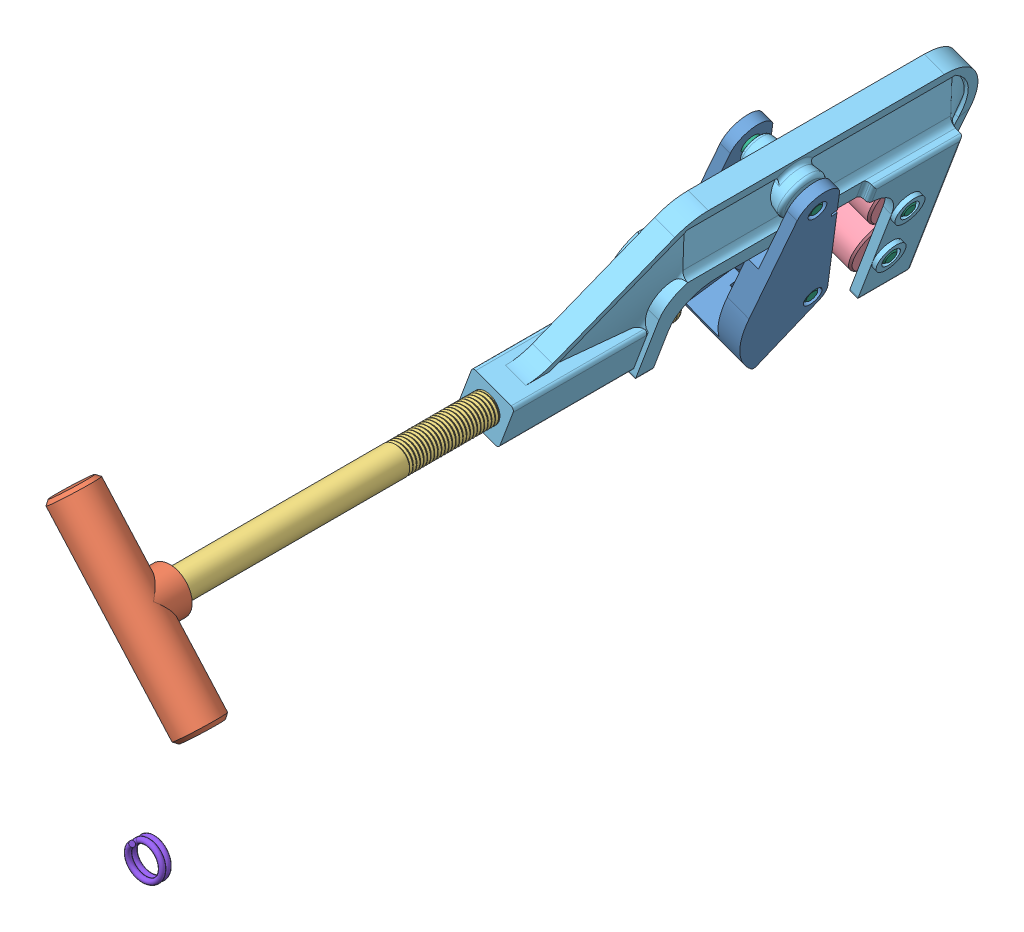
SolidWorks assembly Final_assembly, configuration Default. Lengths in mm.
Overall size (97.39 169.3 489.87).
13 component instances, 8 part files, 18 mates.
Components (placement in the parent):
- Cutter support-1: Cutter support [Default] at (104.9324 19.576 -52.4224) x (0.240047 0.640694 -0.729307) z (-0.936431 0.350851 0) size (81.78 85 46)
- Handle with shaft-1: Handle with shaft [Default] at (247.8061 39.5333 317.841) x (0 0 -1) z (-0.665294 0.746581 0) size (312.5 25 110)
  - Handle-3: Handle [Default<As Welded>] at (32.7874 88.3843 67.7523) size (31 25 110)
  - Handle shaft-1: Handle shaft [Default] at (332.7874 88.3843 122.7523) x (0 0.585455 -0.810705) z (-1 0 0) size (16 18.48 300)
- Roller-1: Roller [Default] at (107.1831 48.3849 -123.2709) x (-0.012894 -0.034413 0.999325) z (-0.936431 0.350851 0) size (30 30 30)
- Frame-2: Frame [Default] at (124.7132 137.9265 -115.2709) x (-0.936431 0.350851 0) z (0 0 1) size (45 115 255.35)
- Roller-2: Roller [Default] at (89.6157 87.0034 -123.2709) x (0.301688 0.805214 -0.510504) z (0.936431 -0.350851 0) size (30 30 30)
- Spring pin-2: Spring pin [Default] at (82.5925 89.6348 -123.2709) x (0.046179 0.123254 -0.9913) z (0.936431 -0.350851 0) size (10 10 45)
- Spring pin-3: Spring pin [Default] at (72.0669 61.5418 -123.2709) x (0.050854 0.135731 -0.98944) z (0.936431 -0.350851 0) size (10 10 45)
- Cutter-1: Cutter [Default] at (95.2554 59.3029 -76.7655) x (0.936431 -0.350851 0) z (0.114408 0.30536 0.945339) size (18 32 32)
- Spring pin-4: Spring pin [Default] at (74.1857 67.197 -76.7655) x (0.123096 0.328548 -0.936431) z (0.936431 -0.350851 0) size (10 10 45)
- Spring pin-5: Spring pin [Default] at (98.3807 131.7742 -55.2709) x (0.123096 0.328548 -0.936431) z (0.936431 -0.350851 0) size (10 10 45)
- spring-1: spring [Default] at (141.3638 -11.2103 316.7484) size (20.51 20.51 9)
Mates (geometry in assembly coordinates):
- Concentric4: concentric: cylinder of Handle with shaft-1/Handle shaft-1 through (100.1537 72.3763 285.0536) axis (0 0 -1) radius 8; cylinder of Frame-2 through (100.1537 72.3763 -5.2709) axis (0 0 1) radius 8
- Concentric5: concentric: cylinder of Cutter support-1 through (97.9125 131.9496 -55.2709) axis (0.936431 -0.350851 0) radius 5; cylinder of Frame-2 through (140.9884 115.8105 -55.2709) axis (-0.936431 0.350851 0) radius 5
- Width2: width: plane of Frame-2 through (133.4969 118.6173 -55.2709) normal (0.936431 -0.350851 0); plane of Frame-2 through (105.404 129.1428 -55.2709) normal (-0.936431 0.350851 0); plane of Cutter support-1 through (100.3548 24.4595 216.8956) normal (-0.936431 0.350851 0); plane of Cutter support-1 through (83.3782 76.0558 227.8805) normal (0.936431 -0.350851 0)
- Concentric6: concentric: cylinder of Roller-1 through (79.0902 58.9105 -123.2709) axis (0.936431 -0.350851 0) radius 5; cylinder of Frame-2 through (133.4032 38.5611 -123.2709) axis (-0.936431 0.350851 0) radius 5
- Coincident1: coincident: plane of Roller-1 through (107.1831 48.3849 -123.2709) normal (0.936431 -0.350851 0); plane of Frame-2 through (128.2342 104.5708 -95.2709) normal (-0.936431 0.350851 0)
- Concentric7: concentric: cylinder of Frame-2 through (143.9287 66.6541 -123.2709) axis (-0.936431 0.350851 0) radius 5; cylinder of Roller-2 through (117.7086 76.4779 -123.2709) axis (-0.936431 0.350851 0) radius 5
- Coincident2: coincident: plane of Frame-2 through (128.2342 104.5708 -95.2709) normal (-0.936431 0.350851 0); plane of Roller-2 through (117.7086 76.4779 -123.2709) normal (0.936431 -0.350851 0)
- Concentric9: concentric: cylinder of Frame-2 through (143.9287 66.6541 -123.2709) axis (-0.936431 0.350851 0) radius 5; cylinder of Spring pin-2 through (124.7319 73.8465 -123.2709) axis (-0.936431 0.350851 0) radius 5
- Coincident3: coincident: plane of Frame-2 through (124.7319 73.8465 -123.2709) normal (0.936431 -0.350851 0); plane of Spring pin-2 through (124.7319 73.8465 -123.2709) normal (0.936431 -0.350851 0)
- Coincident4: coincident: plane of Frame-2 through (82.5925 89.6348 -123.2709) normal (-0.936431 0.350851 0); plane of Spring pin-2 through (82.5925 89.6348 -123.2709) normal (-0.936431 0.350851 0)
- Concentric10: concentric: cylinder of Frame-2 through (133.4032 38.5611 -123.2709) axis (-0.936431 0.350851 0) radius 5; cylinder of Spring pin-3 through (114.2063 45.7536 -123.2709) axis (-0.936431 0.350851 0) radius 5
- Coincident6: coincident: plane of Frame-2 through (72.0669 61.5418 -123.2709) normal (-0.936431 0.350851 0); plane of Spring pin-3 through (72.0669 61.5418 -123.2709) normal (-0.936431 0.350851 0)
- Concentric11: concentric: cylinder of Cutter support-1 through (73.7175 67.3724 -76.7655) axis (0.936431 -0.350851 0) radius 5; cylinder of Cutter-1 through (85.1628 63.0843 -76.7655) axis (-0.936431 0.350851 0) radius 5.05
- Width4: width: plane of Cutter-1 through (103.6833 56.1452 -76.7655) normal (0.936431 -0.350851 0); plane of Cutter-1 through (86.8276 62.4605 -76.7655) normal (-0.936431 0.350851 0); plane of Cutter support-1 through (93.7998 26.9155 216.8956) normal (-0.936431 0.350851 0); plane of Cutter support-1 through (75.0712 33.9325 216.8956) normal (0.936431 -0.350851 0)
- Concentric12: concentric: cylinder of Cutter support-1 through (73.7175 67.3724 -76.7655) axis (0.936431 -0.350851 0) radius 5; cylinder of Spring pin-4 through (116.3252 51.4087 -76.7655) axis (-0.936431 0.350851 0) radius 5
- Width5: width: plane of Spring pin-4 through (116.3252 51.4087 -76.7655) normal (0.936431 -0.350851 0); plane of Spring pin-4 through (74.1857 67.197 -76.7655) normal (-0.936431 0.350851 0); plane of Cutter support-1 through (61.8565 35.7151 -52.4224) normal (-0.936431 0.350851 0); plane of Cutter support-1 through (104.9324 19.576 -52.4224) normal (0.936431 -0.350851 0)
- Concentric13: concentric: cylinder of Cutter support-1 through (97.9125 131.9496 -55.2709) axis (0.936431 -0.350851 0) radius 5; cylinder of Spring pin-5 through (140.5202 115.9859 -55.2709) axis (-0.936431 0.350851 0) radius 5
- Width6: width: plane of Spring pin-5 through (140.5202 115.9859 -55.2709) normal (0.936431 -0.350851 0); plane of Spring pin-5 through (98.3807 131.7742 -55.2709) normal (-0.936431 0.350851 0); plane of Cutter support-1 through (61.8565 35.7151 -52.4224) normal (-0.936431 0.350851 0); plane of Cutter support-1 through (104.9324 19.576 -52.4224) normal (0.936431 -0.350851 0)
